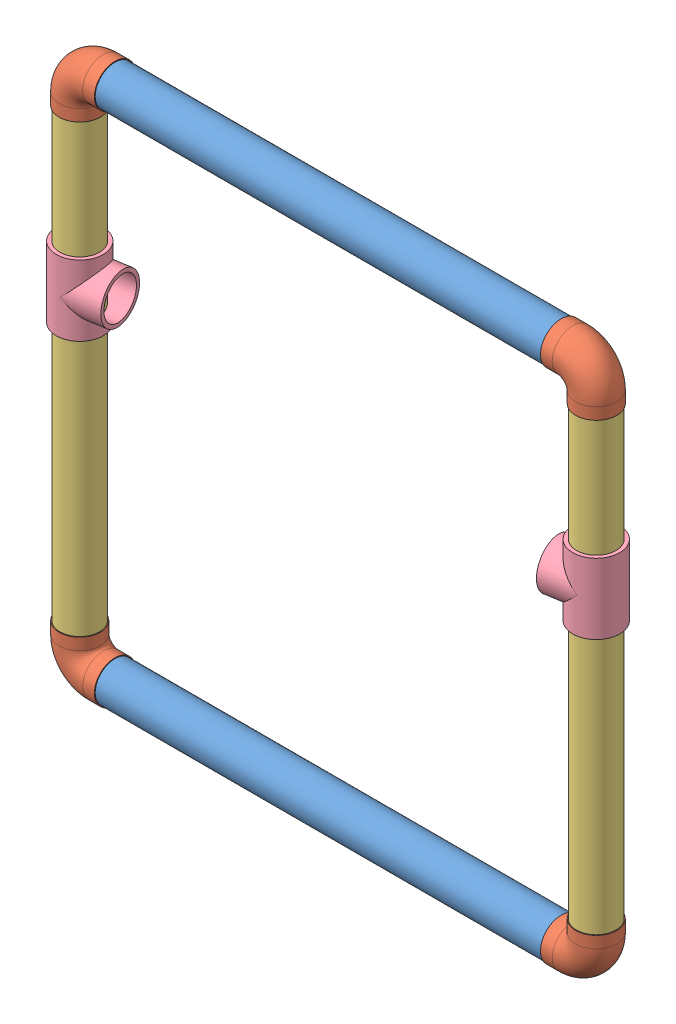
SolidWorks assembly Assem1, configuration Default. Lengths in mm.
Overall size (308.59 301.63 33.58).
10 component instances, 4 part files, 20 mates.
Components (placement in the parent):
- PVC_tube_12in-1: PVC_tube_12in [Default] at (224.9643 139.1096 188.8412) size (254 21.34 21.34)
- PVC_90-1: PVC_90 [Default] at (-23.4538 156.2418 188.8412) size (30.16 30.16 22.23)
- PVC_90-2: PVC_90 [Default] at (220.532 157.3915 188.8412) x (0 1 0) z (0 0 1) size (30.16 30.16 22.23)
- PVC_tube_10in-1: PVC_tube_10in [Default] at (237.6643 151.8096 188.8412) x (0 -1 0) z (0 0 1) size (254 21.34 21.34)
- PVC_90-3: PVC_90 [Default] at (219.3823 401.3774 188.8412) x (-1 0 0) z (0 0 1) size (30.16 30.16 22.23)
- PVC_tube_12in-2: PVC_tube_12in [Default] at (224.9643 418.5096 188.8412) size (254 21.34 21.34)
- PVC_90-4: PVC_90 [Default] at (-24.6035 400.2277 188.8412) x (0 -1 0) z (0 0 1) size (30.16 30.16 22.23)
- PVC_tube_10in-2: PVC_tube_10in [Default] at (-41.7357 405.8096 188.8412) x (0 1 0) z (-0.97697 0 0.213378) size (254 21.34 21.34)
- PVC_tee-1: PVC_tee [Default] at (-41.7357 316.9096 188.8412) x (0 -1 0) z (0.162665 0 0.986681) size (38.1 38.88 25.4)
- PVC_tee-2: PVC_tee [Default] at (237.6643 316.9096 188.8412) x (0 1 0) z (0.162665 0 0.986681) size (38.1 38.88 25.4)
Mates (geometry in assembly coordinates):
- Concentric4: concentric aligned: cylinder of PVC_tube_12in-1 through (-29.0357 139.1096 188.8412) axis (1 0 0) radius 10.668; cylinder of PVC_90-1 through (-29.0357 139.1096 188.8412) axis (1 0 0) radius 10.6807
- Distance2: distance = 6.35 mm anti-aligned: plane of PVC_90-1 through (-22.6857 139.1096 188.8412) normal (1 0 0); plane of PVC_tube_12in-1 through (-29.0357 139.1096 188.8412) normal (-1 0 0)
- Distance3: distance = 6.35 mm anti-aligned: plane of PVC_tube_12in-1 through (224.9643 139.1096 188.8412) normal (1 0 0); plane of PVC_90-2 through (218.6143 139.1096 188.8412) normal (-1 0 0)
- Concentric11: concentric aligned: circle of PVC_tube_12in-1; circle of PVC_90-2
- Distance4: distance = 6.35 mm anti-aligned: plane of PVC_90-2 through (237.6643 158.1596 188.8412) normal (0 1 0); plane of PVC_tube_10in-1 through (237.6643 151.8096 188.8412) normal (0 -1 0)
- Concentric13: concentric anti-aligned: circle of PVC_90-2; circle of PVC_tube_10in-1
- Concentric18: concentric anti-aligned: circle of PVC_tube_10in-1; circle of PVC_90-3
- Distance6: distance = 6.35 mm anti-aligned: plane of PVC_90-3 through (237.6643 399.4596 188.8412) normal (0 -1 0); plane of PVC_tube_10in-1 through (237.6643 405.8096 188.8412) normal (0 1 0)
- Distance7: distance = 6.35 mm anti-aligned: plane of PVC_90-3 through (218.6143 418.5096 188.8412) normal (-1 0 0); plane of PVC_tube_12in-2 through (224.9643 418.5096 188.8412) normal (1 0 0)
- Concentric19: concentric anti-aligned: circle of PVC_90-3; circle of PVC_tube_12in-2
- Distance8: distance = 6.35 mm anti-aligned: plane of PVC_90-4 through (-22.6857 418.5096 188.8412) normal (1 0 0); plane of PVC_tube_12in-2 through (-29.0357 418.5096 188.8412) normal (-1 0 0)
- Concentric20: concentric anti-aligned: circle of PVC_tube_12in-2; circle of PVC_90-4
- Distance9: distance = 6.35 mm anti-aligned: plane of PVC_tube_10in-2 through (-41.7357 405.8096 188.8412) normal (0 1 0); plane of PVC_90-4 through (-41.7357 399.4596 188.8412) normal (0 -1 0)
- Concentric21: concentric anti-aligned: circle of PVC_90-4; circle of PVC_tube_10in-2
- Concentric22: concentric anti-aligned: cylinder of PVC_tube_10in-2 through (-41.7357 151.8096 188.8412) axis (0 1 0) radius 10.668; cylinder of PVC_tee-1 through (-41.7357 335.9596 188.8412) axis (0 -1 0) radius 10.6807
- Parallel13: parallel anti-aligned: plane of PVC_90-1 through (-41.7357 158.1596 188.8412) normal (0 1 0); plane of PVC_tube_10in-2 through (-41.7357 151.8096 188.8412) normal (0 -1 0)
- Distance11: distance = 63.5 mm anti-aligned: plane of PVC_90-4 through (-41.7357 399.4596 188.8412) normal (0 -1 0); plane of PVC_tee-1 through (-41.7357 335.9596 188.8412) normal (0 1 0)
- Parallel14: parallel anti-aligned: line of PVC_tee-1 through (-41.7357 316.9096 188.8412) axis (0.986681 0 -0.162665); line of PVC_tee-2 through (237.6643 316.9096 188.8412) axis (-0.986681 0 0.162665)
- Concentric23: concentric anti-aligned: cylinder of PVC_tube_10in-1 through (237.6643 405.8096 188.8412) axis (0 -1 0) radius 10.668; cylinder of PVC_tee-2 through (237.6643 297.8596 188.8412) axis (0 1 0) radius 10.6807
- Distance12: distance = 63.5 mm anti-aligned: plane of PVC_90-3 through (237.6643 399.4596 188.8412) normal (0 -1 0); plane of PVC_tee-2 through (237.6643 335.9596 188.8412) normal (0 1 0)
